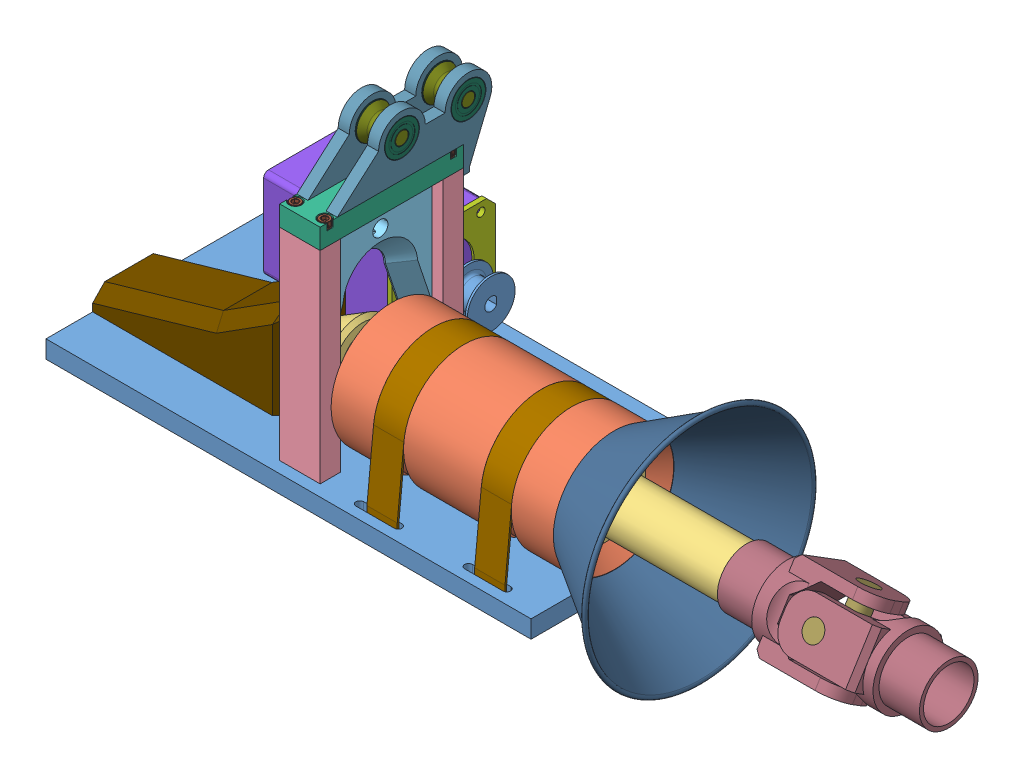
SolidWorks assembly Proto Lock 2.0, configuration Default. Lengths in mm.
Overall size (515.14 212.23 173.25).
40 component instances, 19 part files, 104 mates.
Components (placement in the parent):
- Baseplate V2-1: Baseplate V2 [Default] at (-24.1426 160.6303 305.6707) size (304.8 11.11 152.4)
- 9056K221_Multipurpose_6061_Aluminum_Round_Tube (1)-1: 9056K221_Multipurpose_6061_Aluminum_Round_Tube (1) [9056K221] at (210.8074 209.8428 253.4991) x (0 -0.924225 -0.381849) z (1 0 0) size (76.2 76.2 139.7)
- Male Shaft Pointed-1: Male Shaft Pointed [Default] at (122.7011 209.8428 253.4991) x (0 -0.526299 0.8503) z (1 0 0) size (50.8 50.8 304.8)
- Rail_tapped hole-1: Rail_tapped hole [Default] at (140.9574 171.7428 221.1942) x (-1 0 0) z (0 0 -1) size (25.4 127 12.7)
- Rail_tapped hole-2: Rail_tapped hole [Default] at (115.5574 171.7428 285.8039) size (25.4 127 12.7)
- Lever lock-1: Lever lock [Default] at (122.7011 253.9519 253.4991) x (0 0 -1) z (0 -1 0) size (76.2 11.11 76.2)
- 1x.5 barstock-1: 1x.5 barstock [Default] at (115.5574 311.4428 298.5118) x (1 0 0) z (0 1 0) size (25.4 90.02 12.7)
- Stepper bracket-1: Stepper bracket [Default] at (105.941 171.7428 153.2707) x (-1 0 0) z (0 0 -1) size (68 68 65)
- Stepper-1: Stepper [Default] at (20.941 238.9428 213.9707) x (0 -1 0) z (1 0 0) size (56.4 56.4 104.6)
- Holding Bands-1: Holding Bands [Default] at (235.1362 209.8428 253.4991) x (0 0 -1) z (1 0 0) size (84.14 85.91 19.05)
- Holding Bands-2: Holding Bands [Default] at (167.4285 209.8428 253.4991) x (0 0 -1) z (1 0 0) size (84.14 85.91 19.05)
- 8996T14_24_oz._Tin_Funnel Extrude Cut-1: 8996T14_24_oz._Tin_Funnel Extrude Cut [8996T14] at (259.2124 209.8428 253.4991) x (0 -1 0) z (0 0 1) size (146.05 54.8 146.05)
- 90128A197_Zinc-Plated Alloy Steel Socket Head Screw-5: 90128A197_Zinc-Plated Alloy Steel Socket Head Screw [90128A197] at (119.0499 172.2381 214.8442) x (-0.930632 0 -0.365956) z (0 -1 0) size (6.87 6.87 23.83)
- 90128A197_Zinc-Plated Alloy Steel Socket Head Screw-6: 90128A197_Zinc-Plated Alloy Steel Socket Head Screw [90128A197] at (119.0499 172.2381 292.1539) x (-0.930632 0 -0.365956) z (0 -1 0) size (6.87 6.87 23.83)
- 90128A197_Zinc-Plated Alloy Steel Socket Head Screw-7: 90128A197_Zinc-Plated Alloy Steel Socket Head Screw [90128A197] at (137.4649 172.2381 292.1539) x (-0.930632 0 -0.365956) z (0 -1 0) size (6.87 6.87 23.83)
- 90128A197_Zinc-Plated Alloy Steel Socket Head Screw-8: 90128A197_Zinc-Plated Alloy Steel Socket Head Screw [90128A197] at (137.4649 172.2381 214.8442) x (-0.930632 0 -0.365956) z (0 -1 0) size (6.87 6.87 23.83)
- 90128A197_Zinc-Plated Alloy Steel Socket Head Screw-9: 90128A197_Zinc-Plated Alloy Steel Socket Head Screw [90128A197] at (137.4649 299.835 214.8442) x (-0.837169 0 -0.546944) z (0 1 0) size (6.87 6.87 23.83)
- 90128A197_Zinc-Plated Alloy Steel Socket Head Screw-10: 90128A197_Zinc-Plated Alloy Steel Socket Head Screw [90128A197] at (137.4649 299.835 292.1539) x (-0.837169 0 -0.546944) z (0 1 0) size (6.87 6.87 23.83)
- 90128A197_Zinc-Plated Alloy Steel Socket Head Screw-11: 90128A197_Zinc-Plated Alloy Steel Socket Head Screw [90128A197] at (119.0499 299.835 214.8442) x (-0.837169 0 -0.546944) z (0 1 0) size (6.87 6.87 23.83)
- 90128A197_Zinc-Plated Alloy Steel Socket Head Screw-12: 90128A197_Zinc-Plated Alloy Steel Socket Head Screw [90128A197] at (119.0499 299.835 292.1539) x (-0.462621 0 -0.886556) z (0 1 0) size (6.87 6.87 23.83)
- 90128A197_Zinc-Plated Alloy Steel Socket Head Screw-14: 90128A197_Zinc-Plated Alloy Steel Socket Head Screw [90128A197] at (-5.0926 172.2381 240.7991) x (-0.837169 0 -0.546944) z (0 -1 0) size (6.87 6.87 23.83)
- 90128A197_Zinc-Plated Alloy Steel Socket Head Screw-15: 90128A197_Zinc-Plated Alloy Steel Socket Head Screw [90128A197] at (33.0074 172.2381 240.7991) x (-0.837169 0 -0.546944) z (0 -1 0) size (6.87 6.87 23.83)
- 90128A197_Zinc-Plated Alloy Steel Socket Head Screw-16: 90128A197_Zinc-Plated Alloy Steel Socket Head Screw [90128A197] at (71.1074 172.2381 266.1991) x (-0.837169 0 -0.546944) z (0 -1 0) size (6.87 6.87 23.83)
- 90128A197_Zinc-Plated Alloy Steel Socket Head Screw-17: 90128A197_Zinc-Plated Alloy Steel Socket Head Screw [90128A197] at (33.0074 172.2381 266.1991) x (-0.837169 0 -0.546944) z (0 -1 0) size (6.87 6.87 23.83)
- 90128A197_Zinc-Plated Alloy Steel Socket Head Screw-18: 90128A197_Zinc-Plated Alloy Steel Socket Head Screw [90128A197] at (71.1074 172.2381 240.7991) x (-0.837169 0 -0.546944) z (0 -1 0) size (6.87 6.87 23.83)
- 90128A197_Zinc-Plated Alloy Steel Socket Head Screw-19: 90128A197_Zinc-Plated Alloy Steel Socket Head Screw [90128A197] at (-5.0926 172.2381 266.1991) x (-0.837169 0 -0.546944) z (0 -1 0) size (6.87 6.87 23.83)
- CROSS-1: CROSS [Default] at (427.5011 231.3893 240.0489) x (0 0.529535 0.848288) z (0 -0.848288 0.529535) size (50.8 12.7 50.8)
- ARMS-1: ARMS [Default] at (491.0011 209.8428 253.4991) x (0 0.529535 0.848288) z (0 -0.848288 0.529535) size (50.8 82.55 44.45)
- ARMS-2: ARMS [Default] at (364.0011 209.8428 253.4991) x (0 0.848288 -0.529535) z (0 -0.529535 -0.848288) size (50.8 82.55 44.45)
- Pulley holder-1: Pulley holder [Default] at (115.5574 294.438 241.8411) x (0 0 -1) z (1 0 0) size (97.14 54.49 25.4)
- 5972K222_Ball Bearing-1: 5972K222_Ball Bearing [5972K222] at (137.4574 334.3437 247.0991) x (0 0 -1) z (1 0 0) size (22 22 7)
- 5972K222_Ball Bearing-2: 5972K222_Ball Bearing [5972K222] at (137.4574 334.3437 205.2961) x (0 0 -1) z (1 0 0) size (22 22 7)
- 5972K222_Ball Bearing-3: 5972K222_Ball Bearing [5972K222] at (119.0574 334.3437 205.2961) x (0 0 -1) z (1 0 0) size (22 22 7)
- 5972K222_Ball Bearing-4: 5972K222_Ball Bearing [5972K222] at (119.0574 334.3437 247.0991) x (0 0 -1) z (1 0 0) size (22 22 7)
- Pulley system pulley-1: Pulley system pulley [Default] at (115.5574 338.3061 205.2961) size (25.4 21.38 21.38)
- Pulley system pulley-2: Pulley system pulley [Default] at (115.5574 338.3061 247.0991) size (25.4 21.38 21.38)
- 9002T438_Corrosion-Resistant Precision Compression Springs-1: 9002T438_Corrosion-Resistant Precision Compression Springs [9002T438] at (127.3338 298.7428 287.5355) x (-0.371506 0 0.928431) z (0 1 0) size (12.13 12.13 51.5)
- 9002T438_Corrosion-Resistant Precision Compression Springs-2: 9002T438_Corrosion-Resistant Precision Compression Springs [9002T438] at (128.5908 298.7428 218.0659) x (0.886731 0 -0.462285) z (0 1 0) size (12.13 12.13 51.5)
- Temp Bumper-1: Temp Bumper [Default] at (-24.1426 171.7428 276.3591) size (120.65 60.54 45.72)
- Spool small-1: Spool small [Default] at (128.2574 210.7428 185.7707) x (0 1 0) z (0 0 1) size (30 25 30)
Mates (geometry in assembly coordinates):
- Coincident1: coincident aligned: plane of Baseplate V2-1 through (280.6574 171.7428 305.6707) normal (1 0 0); plane of 9056K221_Multipurpose_6061_Aluminum_Round_Tube (1)-1 through (280.6574 209.8428 253.4991) normal (1 0 0)
- Tangent1: tangent anti-aligned: plane of Baseplate V2-1 through (-24.1426 171.7428 305.6707) normal (0 1 0); cylinder of 9056K221_Multipurpose_6061_Aluminum_Round_Tube (1)-1 through (280.6574 209.8428 253.4991) axis (-1 0 0) radius 38.1
- Width1: width: plane of Baseplate V2-1 through (-24.1426 160.6303 212.5035) normal (0 0 -1); plane of Baseplate V2-1 through (-24.1426 160.6303 294.4947) normal (0 0 1); cylinder of 9056K221_Multipurpose_6061_Aluminum_Round_Tube (1)-1 through (280.6574 209.8428 253.4991) axis (-1 0 0) radius 28.575
- Concentric1: concentric aligned: cylinder of 9056K221_Multipurpose_6061_Aluminum_Round_Tube (1)-1 through (280.6574 209.8428 253.4991) axis (-1 0 0) radius 28.575; cylinder of Male Shaft Pointed-1 through (275.1011 209.8428 253.4991) axis (-1 0 0) radius 25.4
- Concentric2: concentric aligned: circle of Baseplate V2-1; circle of Rail_tapped hole-2
- Concentric3: concentric aligned: circle of Baseplate V2-1; circle of Rail_tapped hole-1
- Concentric4: concentric aligned: circle of Baseplate V2-1; circle of Rail_tapped hole-2
- Concentric7: concentric aligned: cylinder of Baseplate V2-1 through (137.4649 160.6303 214.8442) axis (0 -1 0) radius 2.1526; cylinder of Rail_tapped hole-1 through (137.4649 171.7428 214.8442) axis (0 -1 0) radius 1.7272
- Coincident3: coincident anti-aligned: plane of Baseplate V2-1 through (-24.1426 171.7428 305.6707) normal (0 1 0); plane of Rail_tapped hole-1 through (140.9574 171.7428 221.1942) normal (0 -1 0)
- Coincident4: coincident anti-aligned: plane of Baseplate V2-1 through (-24.1426 171.7428 305.6707) normal (0 1 0); plane of Rail_tapped hole-2 through (115.5574 171.7428 285.8039) normal (0 -1 0)
- Coincident5: coincident anti-aligned: plane of Rail_tapped hole-1 through (140.9574 298.7428 221.1942) normal (0 1 0); plane of 1x.5 barstock-1 through (115.5574 298.7428 208.4942) normal (0 -1 0)
- Concentric8: concentric aligned: cylinder of Rail_tapped hole-1 through (119.0499 298.7428 214.8442) axis (0 1 0) radius 1.7272; cylinder of 1x.5 barstock-1 through (119.0499 311.4428 214.8442) axis (0 1 0) radius 2.1526
- Concentric9: concentric aligned: cylinder of Rail_tapped hole-2 through (119.0499 298.7428 292.1539) axis (0 1 0) radius 1.7272; cylinder of 1x.5 barstock-1 through (119.0499 311.4428 292.1539) axis (0 1 0) radius 2.1526
- Width2: width anti-aligned: plane of Lever lock-1 through (133.8136 253.9519 253.4991) normal (1 0 0); plane of Lever lock-1 through (122.7011 253.9519 253.4991) normal (-1 0 0); plane of Rail_tapped hole-1 through (115.5574 298.7428 221.1942) normal (-1 0 0); plane of Rail_tapped hole-1 through (140.9574 298.7428 221.1942) normal (1 0 0)
- Parallel1: parallel aligned: plane of Rail_tapped hole-2 through (115.5574 298.7428 298.5039) normal (0 0 1); plane of Lever lock-1 through (133.8136 253.9519 291.5991) normal (0 0 1)
- Width3: width aligned: plane of Lever lock-1 through (133.8136 253.9519 291.5991) normal (0 0 1); plane of Lever lock-1 through (133.8136 253.9519 215.3991) normal (0 0 -1); plane of Rail_tapped hole-2 through (115.5574 298.7428 298.5039) normal (0 0 1); plane of Rail_tapped hole-1 through (140.9574 298.7428 208.4942) normal (0 0 -1)
- Coincident7: coincident anti-aligned: plane of Baseplate V2-1 through (-24.1426 171.7428 305.6707) normal (0 1 0); plane of Stepper bracket-1 through (105.941 171.7428 153.2707) normal (0 -1 0)
- Parallel2: parallel anti-aligned: plane of Rail_tapped hole-1 through (115.5574 298.7428 221.1942) normal (-1 0 0); plane of Stepper bracket-1 through (105.941 239.7428 153.2707) normal (1 0 0)
- Coincident11: coincident aligned: plane of Baseplate V2-1 through (-24.1426 171.7428 153.2707) normal (0 0 -1); plane of Stepper bracket-1 through (105.941 239.7428 153.2707) normal (0 0 -1)
- Concentric19: concentric anti-aligned: cylinder of 9056K221_Multipurpose_6061_Aluminum_Round_Tube (1)-1 through (280.6574 209.8428 253.4991) axis (1 0 0) radius 35.56; cylinder of Holding Bands-1 through (254.1862 209.8428 253.4991) axis (-1 0 0) radius 38.1
- Parallel3: parallel aligned: plane of Baseplate V2-1 through (232.5955 163.1703 153.2697) normal (0 -1 0); plane of Holding Bands-1 through (254.1862 162.0353 295.567) normal (0 -1 0)
- Concentric20: concentric anti-aligned: cylinder of 9056K221_Multipurpose_6061_Aluminum_Round_Tube (1)-1 through (280.6574 209.8428 253.4991) axis (1 0 0) radius 35.56; cylinder of Holding Bands-2 through (186.4785 209.8428 253.4991) axis (-1 0 0) radius 37.465
- Parallel4: parallel aligned: plane of Baseplate V2-1 through (164.2695 163.3081 153.2697) normal (0 -1 0); plane of Holding Bands-2 through (186.4785 162.0353 295.567) normal (0 -1 0)
- Concentric21: concentric anti-aligned: cylinder of 9056K221_Multipurpose_6061_Aluminum_Round_Tube (1)-1 through (280.6574 209.8428 253.4991) axis (-1 0 0) radius 38.1; circle of 8996T14_24_oz._Tin_Funnel Extrude Cut-1
- Coincident14: coincident anti-aligned: plane of 9056K221_Multipurpose_6061_Aluminum_Round_Tube (1)-1 through (280.6574 209.8428 253.4991) normal (1 0 0); plane of 8996T14_24_oz._Tin_Funnel Extrude Cut-1 through (280.6574 171.7305 180.4741) normal (-1 0 0)
- Concentric22: concentric aligned: cylinder of Baseplate V2-1 through (88.7107 160.6303 193.2707) axis (0 -1 0) radius 3.9688; cylinder of 90128A197_Zinc-Plated Alloy Steel Socket Head Screw-1 through (88.7107 160.6303 193.2707) axis (0 -1 0) radius 3.429
- Coincident15: coincident aligned: plane of Baseplate V2-1 through (-24.1426 160.6303 305.6707) normal (0 -1 0); plane of 90128A197_Zinc-Plated Alloy Steel Socket Head Screw-1 through (90.9025 160.6303 191.0714) normal (0 -1 0)
- Concentric23: concentric aligned: cylinder of Baseplate V2-1 through (103.7107 160.6303 163.2707) axis (0 -1 0) radius 3.9688; cylinder of 90128A197_Zinc-Plated Alloy Steel Socket Head Screw-2 through (103.7107 160.6303 163.2707) axis (0 -1 0) radius 3.429
- Coincident16: coincident aligned: plane of Baseplate V2-1 through (-24.1426 160.6303 305.6707) normal (0 -1 0); plane of 90128A197_Zinc-Plated Alloy Steel Socket Head Screw-2 through (105.0854 160.6303 160.4866) normal (0 -1 0)
- Concentric24: concentric aligned: cylinder of Baseplate V2-1 through (103.5574 160.6303 193.2707) axis (0 -1 0) radius 3.9688; cylinder of 90128A197_Zinc-Plated Alloy Steel Socket Head Screw-4 through (103.5574 160.6303 193.2707) axis (0 -1 0) radius 3.429
- Coincident17: coincident aligned: plane of Baseplate V2-1 through (-24.1426 160.6303 305.6707) normal (0 -1 0); plane of 90128A197_Zinc-Plated Alloy Steel Socket Head Screw-4 through (104.6937 160.6303 190.3811) normal (0 -1 0)
- Coincident18: coincident aligned: plane of Baseplate V2-1 through (-24.1426 160.6303 305.6707) normal (0 -1 0); plane of 90128A197_Zinc-Plated Alloy Steel Socket Head Screw-3 through (86.0892 160.6303 161.6068) normal (0 -1 0)
- Concentric27: concentric aligned: cylinder of Baseplate V2-1 through (137.4649 160.6303 292.1539) axis (0 -1 0) radius 3.9688; cylinder of 90128A197_Zinc-Plated Alloy Steel Socket Head Screw-7 through (137.4649 160.6303 292.1539) axis (0 -1 0) radius 3.429
- Concentric28: concentric aligned: cylinder of Baseplate V2-1 through (137.4649 160.6303 214.8442) axis (0 -1 0) radius 3.9688; cylinder of 90128A197_Zinc-Plated Alloy Steel Socket Head Screw-8 through (137.4649 160.6303 214.8442) axis (0 -1 0) radius 3.429
- Concentric29: concentric aligned: cylinder of Baseplate V2-1 through (119.0499 160.6303 292.1539) axis (0 -1 0) radius 3.9688; cylinder of 90128A197_Zinc-Plated Alloy Steel Socket Head Screw-6 through (119.0499 160.6303 292.1539) axis (0 -1 0) radius 3.429
- Concentric30: concentric aligned: cylinder of Baseplate V2-1 through (119.0499 160.6303 214.8442) axis (0 -1 0) radius 3.9688; cylinder of 90128A197_Zinc-Plated Alloy Steel Socket Head Screw-5 through (119.0499 160.6303 214.8442) axis (0 -1 0) radius 3.429
- Coincident19: coincident aligned: plane of Baseplate V2-1 through (-24.1426 160.6303 305.6707) normal (0 -1 0); plane of 90128A197_Zinc-Plated Alloy Steel Socket Head Screw-5 through (120.1862 160.6303 211.9547) normal (0 -1 0)
- Coincident20: coincident aligned: plane of Baseplate V2-1 through (-24.1426 160.6303 305.6707) normal (0 -1 0); plane of 90128A197_Zinc-Plated Alloy Steel Socket Head Screw-8 through (138.6012 160.6303 211.9547) normal (0 -1 0)
- Coincident21: coincident aligned: plane of Baseplate V2-1 through (-24.1426 160.6303 305.6707) normal (0 -1 0); plane of 90128A197_Zinc-Plated Alloy Steel Socket Head Screw-6 through (120.1862 160.6303 289.2643) normal (0 -1 0)
- Coincident22: coincident aligned: plane of Baseplate V2-1 through (-24.1426 160.6303 305.6707) normal (0 -1 0); plane of 90128A197_Zinc-Plated Alloy Steel Socket Head Screw-7 through (138.6012 160.6303 289.2643) normal (0 -1 0)
- Concentric31: concentric aligned: cylinder of 1x.5 barstock-1 through (137.4649 311.4428 214.8442) axis (0 1 0) radius 3.9688; cylinder of 90128A197_Zinc-Plated Alloy Steel Socket Head Screw-9 through (137.4649 311.4428 214.8442) axis (0 1 0) radius 3.429
- Concentric32: concentric aligned: cylinder of 1x.5 barstock-1 through (119.0499 311.4428 214.8442) axis (0 1 0) radius 3.9688; cylinder of 90128A197_Zinc-Plated Alloy Steel Socket Head Screw-11 through (119.0499 311.4428 214.8442) axis (0 1 0) radius 3.429
- Concentric33: concentric aligned: cylinder of 1x.5 barstock-1 through (137.4649 311.4428 292.1539) axis (0 1 0) radius 3.9688; cylinder of 90128A197_Zinc-Plated Alloy Steel Socket Head Screw-10 through (137.4649 311.4428 292.1539) axis (0 1 0) radius 3.429
- Concentric34: concentric aligned: cylinder of 1x.5 barstock-1 through (119.0499 311.4428 292.1539) axis (0 1 0) radius 3.9688; cylinder of 90128A197_Zinc-Plated Alloy Steel Socket Head Screw-12 through (119.0499 311.4428 292.1539) axis (0 1 0) radius 3.429
- Coincident23: coincident aligned: plane of 1x.5 barstock-1 through (115.5574 311.4428 208.4942) normal (0 1 0); plane of 90128A197_Zinc-Plated Alloy Steel Socket Head Screw-11 through (117.3516 311.4428 217.4436) normal (0 1 0)
- Coincident24: coincident aligned: plane of 1x.5 barstock-1 through (115.5574 311.4428 208.4942) normal (0 1 0); plane of 90128A197_Zinc-Plated Alloy Steel Socket Head Screw-9 through (135.7666 311.4428 217.4436) normal (0 1 0)
- Coincident25: coincident aligned: plane of 1x.5 barstock-1 through (115.5574 311.4428 208.4942) normal (0 1 0); plane of 90128A197_Zinc-Plated Alloy Steel Socket Head Screw-12 through (116.2972 311.4428 293.5903) normal (0 1 0)
- Coincident26: coincident aligned: plane of 1x.5 barstock-1 through (115.5574 311.4428 208.4942) normal (0 1 0); plane of 90128A197_Zinc-Plated Alloy Steel Socket Head Screw-10 through (135.7666 311.4428 294.7533) normal (0 1 0)
- Concentric35: concentric aligned: cylinder of Lever lock-1 through (128.2574 292.0519 253.4991) axis (0 1 0) radius 1.7272; cylinder of 90128A197_Zinc-Plated Alloy Steel Socket Head Screw-13 through (128.2574 257.2391 253.4991) axis (0 1 0) radius 3.429
- Distance1: distance = 6 mm anti-aligned: plane of 90128A197_Zinc-Plated Alloy Steel Socket Head Screw-13 through (127.5816 253.0735 255.4692) normal (0 -1 0); plane of Lever lock-1 through (133.8136 292.0519 253.4991) normal (0 1 0)
- Concentric36: concentric aligned: cylinder of Baseplate V2-1 through (-5.0926 160.6303 266.1991) axis (0 -1 0) radius 3.9688; cylinder of 90128A197_Zinc-Plated Alloy Steel Socket Head Screw-19 through (-5.0926 160.6303 266.1991) axis (0 -1 0) radius 3.429
- Concentric37: concentric aligned: circle of Baseplate V2-1; cylinder of 90128A197_Zinc-Plated Alloy Steel Socket Head Screw-14 through (-5.0926 160.6303 240.7991) axis (0 -1 0) radius 3.429
- Concentric38: concentric aligned: cylinder of Baseplate V2-1 through (33.0074 160.6303 240.7991) axis (0 -1 0) radius 3.9688; cylinder of 90128A197_Zinc-Plated Alloy Steel Socket Head Screw-15 through (33.0074 160.6303 240.7991) axis (0 -1 0) radius 3.429
- Concentric39: concentric aligned: cylinder of Baseplate V2-1 through (33.0074 160.6303 266.1991) axis (0 -1 0) radius 3.9688; cylinder of 90128A197_Zinc-Plated Alloy Steel Socket Head Screw-17 through (33.0074 160.6303 266.1991) axis (0 -1 0) radius 3.429
- Concentric40: concentric aligned: cylinder of Baseplate V2-1 through (71.1074 160.6303 240.7991) axis (0 -1 0) radius 3.9688; circle of 90128A197_Zinc-Plated Alloy Steel Socket Head Screw-18
- Concentric41: concentric aligned: cylinder of Baseplate V2-1 through (71.1074 160.6303 266.1991) axis (0 -1 0) radius 3.9688; cylinder of 90128A197_Zinc-Plated Alloy Steel Socket Head Screw-16 through (71.1074 160.6303 266.1991) axis (0 -1 0) radius 3.429
- Coincident28: coincident anti-aligned: plane of Baseplate V2-1 through (-2.94 164.7959 266.1991) normal (0 -1 0); plane of 90128A197_Zinc-Plated Alloy Steel Socket Head Screw-19 through (-3.9534 164.7959 264.4554) normal (0 1 0)
- Coincident29: coincident anti-aligned: plane of Baseplate V2-1 through (-2.94 164.7959 240.7991) normal (0 -1 0); plane of 90128A197_Zinc-Plated Alloy Steel Socket Head Screw-14 through (-3.9534 164.7959 239.0554) normal (0 1 0)
- Coincident30: coincident anti-aligned: plane of Baseplate V2-1 through (35.16 164.7959 266.1991) normal (0 -1 0); plane of 90128A197_Zinc-Plated Alloy Steel Socket Head Screw-17 through (34.1466 164.7959 264.4554) normal (0 1 0)
- Coincident31: coincident anti-aligned: plane of Baseplate V2-1 through (35.16 164.7959 240.7991) normal (0 -1 0); plane of 90128A197_Zinc-Plated Alloy Steel Socket Head Screw-15 through (34.1466 164.7959 239.0554) normal (0 1 0)
- Coincident32: coincident anti-aligned: plane of Baseplate V2-1 through (73.26 164.7959 266.1991) normal (0 -1 0); plane of 90128A197_Zinc-Plated Alloy Steel Socket Head Screw-16 through (72.2466 164.7959 264.4554) normal (0 1 0)
- Coincident33: coincident anti-aligned: plane of Baseplate V2-1 through (73.26 164.7959 240.7991) normal (0 -1 0); plane of 90128A197_Zinc-Plated Alloy Steel Socket Head Screw-18 through (72.2466 164.7959 239.0554) normal (0 1 0)
- Concentric42: concentric aligned: cylinder of Male Shaft Pointed-1 through (389.4011 209.8428 253.4991) axis (-1 0 0) radius 15.875; cylinder of ARMS-2 through (389.4011 209.8428 253.4991) axis (-1 0 0) radius 15.875
- Coincident34: coincident anti-aligned: plane of Male Shaft Pointed-1 through (389.4011 209.8428 253.4991) normal (1 0 0); plane of ARMS-2 through (389.4011 209.8428 253.4991) normal (-1 0 0)
- Concentric43: concentric anti-aligned: cylinder of CROSS-1 through (427.5011 188.2963 266.9492) axis (0 0.848288 -0.529535) radius 6.35; cylinder of ARMS-2 through (427.5011 231.3893 240.0489) axis (0 -0.848288 0.529535) radius 6.35
- Coincident35: coincident aligned: plane of CROSS-1 through (427.5011 231.3893 240.0489) normal (0 0.848288 -0.529535); plane of ARMS-2 through (446.5511 222.983 226.5823) normal (0 0.848288 -0.529535)
- Coincident36: coincident aligned: plane of CROSS-1 through (427.5011 223.293 275.0456) normal (0 0.529535 0.848288); plane of ARMS-1 through (408.4511 209.8264 283.4519) normal (0 0.529535 0.848288)
- Concentric44: concentric anti-aligned: cylinder of CROSS-1 through (427.5011 196.3926 231.9525) axis (0 0.529535 0.848288) radius 6.35; cylinder of ARMS-1 through (427.5011 223.293 275.0456) axis (0 -0.529535 -0.848288) radius 6.35
- Concentric45: concentric anti-aligned: cylinder of Male Shaft Pointed-1 through (389.4011 209.8428 253.4991) axis (-1 0 0) radius 15.875; cylinder of ARMS-1 through (465.6011 209.8428 253.4991) axis (1 0 0) radius 18.415
- Coincident37: coincident anti-aligned: plane of 9056K221_Multipurpose_6061_Aluminum_Round_Tube (1)-1 through (167.4285 209.8428 253.4991) normal (1 0 0); plane of Holding Bands-2 through (167.4285 209.8428 253.4991) normal (-1 0 0)
- Coincident38: coincident anti-aligned: plane of 9056K221_Multipurpose_6061_Aluminum_Round_Tube (1)-1 through (235.1362 209.8428 253.4991) normal (1 0 0); plane of Holding Bands-1 through (235.1362 209.8428 253.4991) normal (-1 0 0)
- Coincident39: coincident anti-aligned: plane of Male Shaft Pointed-1 through (122.7011 199.044 246.8151) normal (1 0 0); plane of Lever lock-1 through (122.7011 253.9519 253.4991) normal (-1 0 0)
- Concentric46: concentric aligned: cylinder of Stepper bracket-1 through (105.941 210.7428 185.7707) axis (-1 0 0) radius 19.1; cylinder of Stepper-1 through (104.541 210.7428 185.7707) axis (-1 0 0) radius 19.05
- Coincident40: coincident anti-aligned: plane of Stepper bracket-1 through (102.941 171.7428 218.2707) normal (-1 0 0); plane of Stepper-1 through (102.941 238.9428 213.9707) normal (1 0 0)
- Parallel5: parallel aligned: plane of Stepper bracket-1 through (105.941 239.7428 153.2707) normal (0 0 -1); plane of Stepper-1 through (102.941 238.9428 157.5707) normal (0 0 -1)
- Concentric47: concentric anti-aligned: cylinder of Stepper-1 through (125.541 210.7428 185.7707) axis (-1 0 0) radius 4; cylinder of Spool-1 through (110.7574 210.7428 185.7707) axis (1 0 0) radius 7.5
- Parallel6: parallel anti-aligned: plane of Stepper-1 through (119.0556 221.2428 182.2707) normal (0 0 -1); plane of Spool-1 through (120.7574 210.7428 182.3207) normal (0 0 1)
- Coincident43: coincident anti-aligned: plane of Stepper-1 through (110.7574 221.2428 182.2707) normal (1 0 0); circle of Spool-1
- Width4: width aligned: plane of Rail_tapped hole-1 through (140.9574 298.7428 221.1942) normal (1 0 0); plane of Spool-1 through (115.5574 298.7428 221.1942) normal (-1 0 0); plane of Rail_tapped hole-1 through (135.7574 210.7428 185.7707) normal (1 0 0); plane of Spool-1 through (120.7574 210.7428 185.7707) normal (-1 0 0)
- Coincident44: coincident anti-aligned: plane of 1x.5 barstock-1 through (115.5574 311.4428 208.4942) normal (0 1 0); plane of Pulley holder-1 through (140.9574 311.4428 241.8411) normal (0 -1 0)
- Coincident45: coincident anti-aligned: plane of Rail_tapped hole-1 through (140.9574 298.7428 208.4942) normal (0 0 -1); plane of Pulley holder-1 through (140.9574 294.438 208.4942) normal (0 0 1)
- Coincident46: coincident aligned: plane of 1x.5 barstock-1 through (140.9574 311.4428 208.4942) normal (1 0 0); plane of Pulley holder-1 through (140.9574 294.438 241.8411) normal (1 0 0)
- Concentric48: concentric anti-aligned: cylinder of Pulley holder-1 through (140.9574 334.3437 247.0991) axis (-1 0 0) radius 10.9728; cylinder of 5972K222_Ball Bearing-1 through (140.9574 334.3437 247.0991) axis (1 0 0) radius 11
- Coincident47: coincident aligned: plane of Pulley holder-1 through (140.9574 294.438 241.8411) normal (1 0 0); plane of 5972K222_Ball Bearing-1 through (140.9574 344.9937 247.0991) normal (1 0 0)
- Concentric49: concentric anti-aligned: cylinder of Pulley holder-1 through (140.9574 334.3437 247.0991) axis (-1 0 0) radius 10.9728; cylinder of 5972K222_Ball Bearing-4 through (122.5574 334.3437 247.0991) axis (1 0 0) radius 11
- Coincident48: coincident aligned: plane of Pulley holder-1 through (115.5574 294.438 241.8411) normal (-1 0 0); plane of 5972K222_Ball Bearing-4 through (115.5574 344.9937 247.0991) normal (-1 0 0)
- Concentric50: concentric anti-aligned: cylinder of Pulley holder-1 through (140.9574 334.3437 205.2961) axis (-1 0 0) radius 10.9728; cylinder of 5972K222_Ball Bearing-3 through (122.5574 334.3437 205.2961) axis (1 0 0) radius 11
- Concentric51: concentric anti-aligned: cylinder of Pulley holder-1 through (140.9574 334.3437 205.2961) axis (-1 0 0) radius 10.9728; cylinder of 5972K222_Ball Bearing-2 through (140.9574 334.3437 205.2961) axis (1 0 0) radius 11
- Coincident49: coincident aligned: plane of Pulley holder-1 through (140.9574 294.438 241.8411) normal (1 0 0); plane of 5972K222_Ball Bearing-2 through (140.9574 344.9937 205.2961) normal (1 0 0)
- Coincident50: coincident aligned: plane of Pulley holder-1 through (115.5574 294.438 241.8411) normal (-1 0 0); plane of 5972K222_Ball Bearing-3 through (115.5574 344.9937 205.2961) normal (-1 0 0)
- Concentric52: concentric aligned: cylinder of 5972K222_Ball Bearing-2 through (140.9574 334.3437 205.2961) axis (1 0 0) radius 4; cylinder of Pulley system pulley-1 through (140.9574 334.3437 205.2961) axis (1 0 0) radius 3.9624
- Coincident52: coincident aligned: plane of Pulley holder-1 through (140.9574 294.438 241.8411) normal (1 0 0); plane of Pulley system pulley-1 through (140.9574 338.3061 205.2961) normal (1 0 0)
- Concentric53: concentric aligned: cylinder of 5972K222_Ball Bearing-4 through (122.5574 334.3437 247.0991) axis (1 0 0) radius 4; cylinder of Pulley system pulley-2 through (140.9574 334.3437 247.0991) axis (1 0 0) radius 3.9624
- Coincident53: coincident aligned: plane of Pulley holder-1 through (115.5574 294.438 241.8411) normal (-1 0 0); plane of Pulley system pulley-2 through (115.5574 334.3437 247.0991) normal (-1 0 0)
- Coincident54: coincident anti-aligned: plane of 1x.5 barstock-1 through (115.5574 298.7428 208.4942) normal (0 -1 0); plane of 9002T438_Corrosion-Resistant Precision Compression Springs-1 through (129.3154 298.7428 282.5832) normal (0 1 0)
- Tangent2: tangent anti-aligned: plane of Rail_tapped hole-2 through (115.5574 298.7428 292.8691) normal (0 0 -1); face of 9002T438_Corrosion-Resistant Precision Compression Springs-1
- Coincident55: coincident anti-aligned: plane of 1x.5 barstock-1 through (115.5574 298.7428 208.4942) normal (0 -1 0); plane of 9002T438_Corrosion-Resistant Precision Compression Springs-2 through (123.8609 298.7428 220.5317) normal (0 1 0)
- Tangent5: tangent aligned: plane of Rail_tapped hole-1 through (140.9574 298.7428 214.1291) normal (0 0 1); edge_curve of 9002T438_Corrosion-Resistant Precision Compression Springs-2
- Coincident57: coincident aligned: plane of Baseplate V2-1 through (-24.1426 171.7428 305.6707) normal (-1 0 0); plane of Temp Bumper-1 through (-24.1426 184.4428 276.3591) normal (-1 0 0)
- Concentric54: concentric aligned: cylinder of Baseplate V2-1 through (-5.0926 160.6303 240.7991) axis (0 -1 0) radius 3.9688; cylinder of Temp Bumper-1 through (-5.0926 184.4428 240.7991) axis (0 -1 0) radius 1.7272
- Concentric55: concentric aligned: cylinder of Baseplate V2-1 through (71.1074 160.6303 266.1991) axis (0 -1 0) radius 3.9688; cylinder of Temp Bumper-1 through (71.1074 184.4428 266.1991) axis (0 -1 0) radius 1.7272
- Coincident58: coincident anti-aligned: plane of Baseplate V2-1 through (-24.1426 171.7428 305.6707) normal (0 1 0); plane of Temp Bumper-1 through (-24.1426 171.7428 276.3591) normal (0 -1 0)
- Concentric56: concentric anti-aligned: cylinder of Stepper-1 through (125.541 210.7428 185.7707) axis (-1 0 0) radius 4; cylinder of Spool small-1 through (120.7574 210.7428 185.7707) axis (1 0 0) radius 4.05
- Width5: width aligned: plane of Spool small-1 through (122.0814 210.7428 185.7707) normal (1 0 0); plane of Rail_tapped hole-1 through (134.4334 210.7428 185.7707) normal (-1 0 0); plane of Spool small-1 through (140.9574 298.7428 221.1942) normal (1 0 0); plane of Rail_tapped hole-1 through (115.5574 298.7428 221.1942) normal (-1 0 0)
